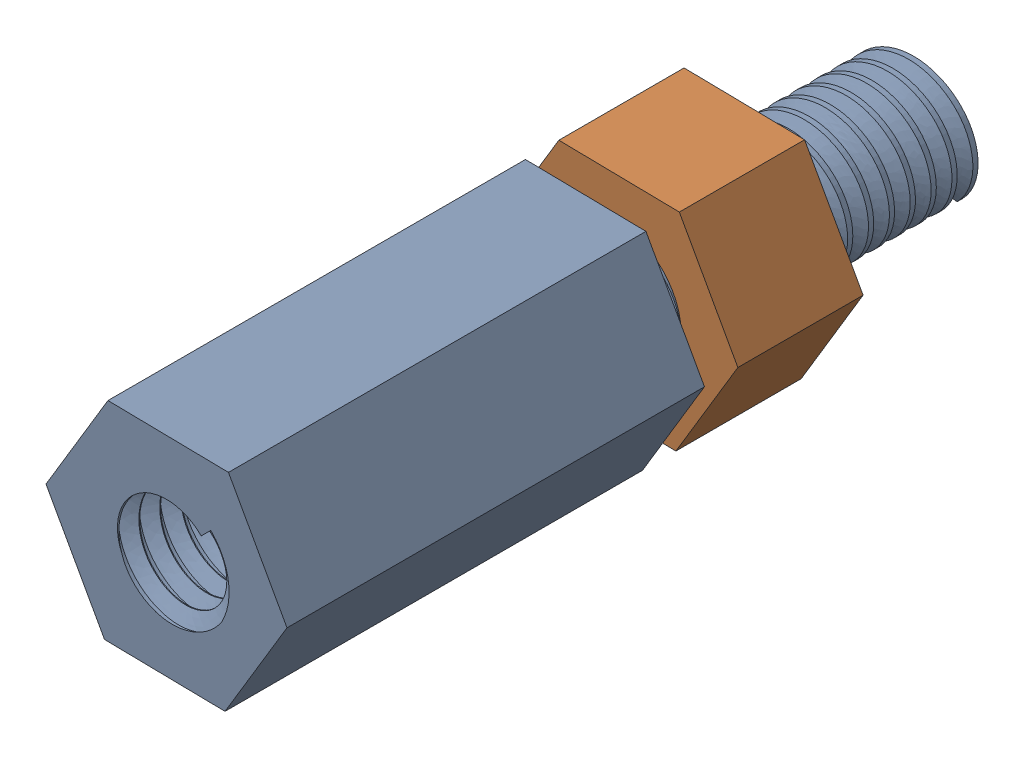
SolidWorks assembly HOLE1, configuration Défaut. Lengths in mm.
Overall size (5.77 5.05 18.25).
2 component instances, 2 part files, 0 mates.
Components (placement in the parent):
- User_Library-Spacer-M3-10mm-1: User_Library-Spacer-M3-10mm [Défaut] at (25.0001 75.0001 0) x (1 0 0) z (0 -1 0) size (5.77 18.25 5.05)
- User_Library-Female_screw_M3-1: User_Library-Female_screw_M3 [Défaut] at (25.0001 75.0001 -3.8) x (1 0 0) z (0 -1 0) size (5.77 3 5.05)
